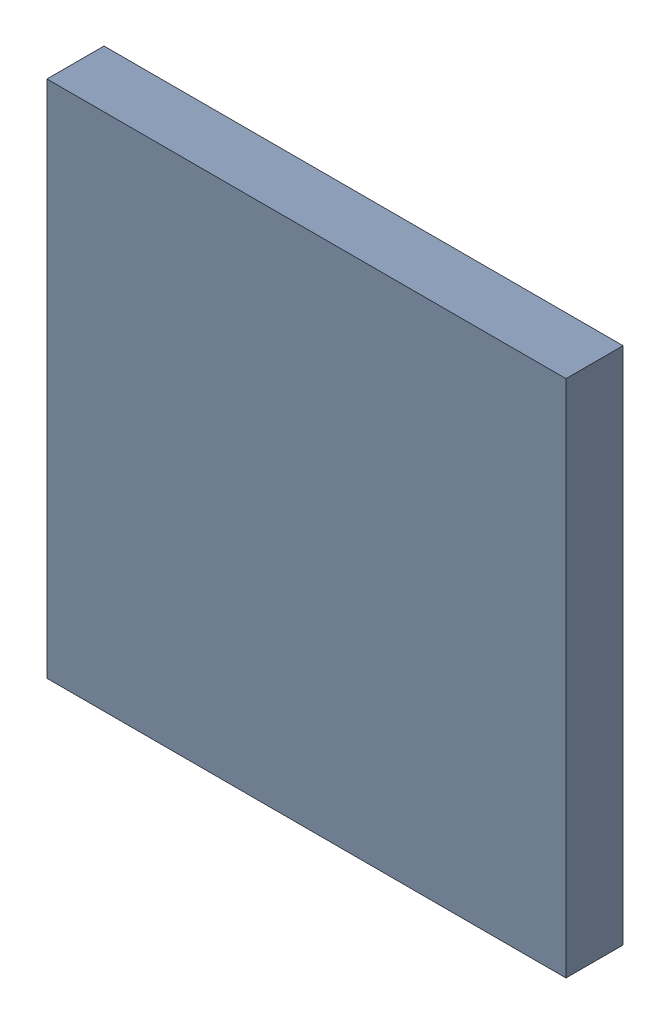
SolidWorks assembly U9, configuration ﾃﾞﾌｫﾙﾄ. Lengths in mm.
Overall size (5 5 0.55).
2 component instances, 1 part files, 0 mates.
Components (placement in the parent):
- 689262192-1: 689262192 [ﾃﾞﾌｫﾙﾄ] at (52.4 24.6 0) size (5 5 0.55)
  - Extruded_38-1: Extruded_38 [ﾃﾞﾌｫﾙﾄ] at origin size (5 5 0.55)
